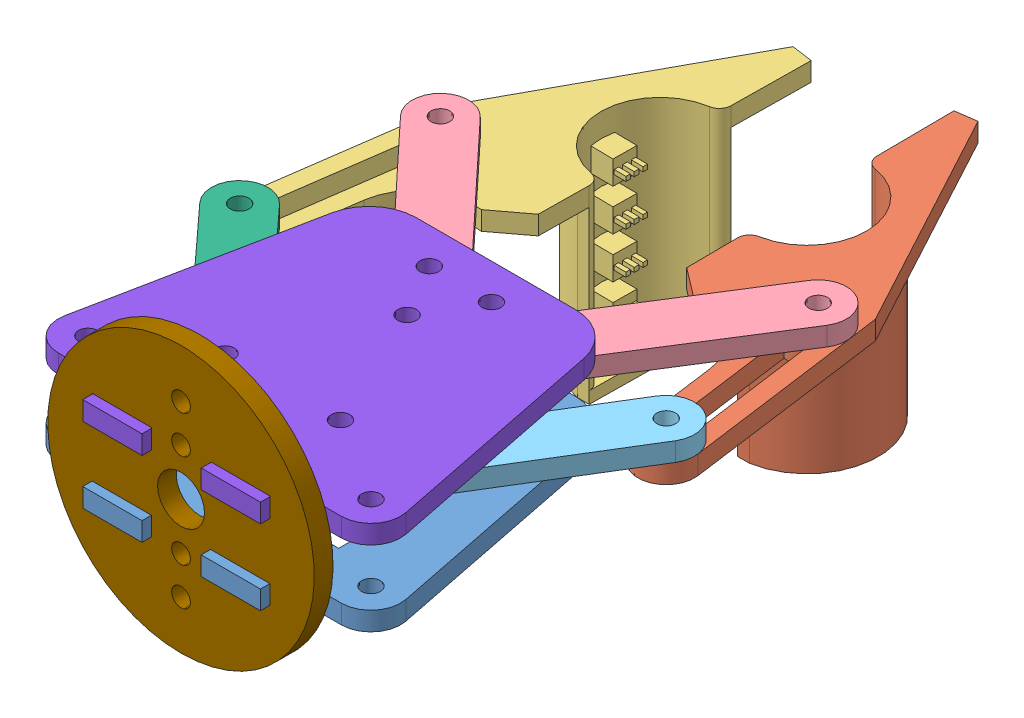
SolidWorks assembly Gripper2, configuration Predeterminado. Lengths in mm.
Overall size (91.5 56.15 127.82).
15 component instances, 9 part files, 33 mates.
Components (placement in the parent):
- Base grip-1: Base grip [Predeterminado] at (-28.7905 -8.0804 25) size (57.8 3.17 54.76)
- Gripp2-3: Gripp2 [Predeterminado] at (19.4575 -1.7304 -56.7394) x (-0.990815 0 0.135226) z (0.135226 0 0.990815) size (24.38 32 79.76)
- Gripp-3: Gripp [Predeterminado] at (-23.0143 -4.9054 -52.0769) x (0.99023 0 0.139447) z (-0.139447 0 0.99023) size (24.38 32 79.76)
- eslabon dos-1: eslabon dos [Predeterminado] at (13.1017 -1.7304 -38.4567) x (0.533516 0 -0.84579) z (0.84579 0 0.533516) size (49.52 3.17 9.53)
- eslabon dos-2: eslabon dos [Predeterminado] at (-14.2298 -1.7304 -36.8567) x (0.683322 0 0.730117) z (-0.730117 0 0.683322) size (49.52 3.17 9.53)
- eslabon engrane servo-1: eslabon engrane servo [Predeterminado] at (25.469 -1.7304 -3.5655) x (-0.522435 0 0.852679) z (-0.852679 0 -0.522435) size (56.02 3.17 23.48)
- eslabon engrane servo - copia-1: eslabon engrane servo - copia [Predeterminado] at (-18.5366 -1.7304 -6.9655) x (0.675407 0 0.737445) z (-0.737445 0 0.675407) size (56.51 3.17 22.67)
- separadores-1: separadores [Predeterminado] at (-8.5405 -4.9054 11) x (0.999665 0 -0.025874) z (0.025874 0 0.999665) size (6.35 3.17 6.35)
- separadores-2: separadores [Predeterminado] at (-8.5405 1.4446 11) x (0.999761 0 0.021872) z (-0.021872 0 0.999761) size (6.35 3.17 6.35)
- separadores-4: separadores [Predeterminado] at (-4.0405 -4.9054 -19) x (0.999761 0 0.021872) z (-0.021872 0 0.999761) size (6.35 3.17 6.35)
- separadores-5: separadores [Predeterminado] at (6.4595 1.4446 -19) x (0.999761 0 0.021872) z (-0.021872 0 0.999761) size (6.35 3.17 6.35)
- separadores-6: separadores [Predeterminado] at (-4.0405 1.4446 -19) x (0.999761 0 0.021872) z (-0.021872 0 0.999761) size (6.35 3.17 6.35)
- separadores-7: separadores [Predeterminado] at (6.4595 -4.9054 -19) x (0.999761 0 0.021872) z (-0.021872 0 0.999761) size (6.35 3.17 6.35)
- bse grip superior-2: bse grip superior [Predeterminado] at (-28.7905 4.6196 25) size (57.8 3.17 54.76)
- base gripper servo-1: base gripper servo [Predeterminado] at (1.2095 -0.0804 28.175) x (1 0 0) z (0 1 0) size (45 3.17 45)
Mates (geometry in assembly coordinates):
- Coincidente33: coincident aligned: axis of Base grip-1 through (-4.0405 -4.9054 -19) axis (0 -1 0); axis of eslabon dos-2 through (-4.0405 1.4446 -19) axis (0 -1 0)
- Coincidente38: coincident aligned: axis of Gripp-3 through (-31.3734 -1.7304 -48.2047) axis (0 -1 0); axis of eslabon dos-2 through (-31.3734 1.4446 -48.2047) axis (0 -1 0)
- Coincidente43: coincident anti-aligned: axis of Gripp2-3 through (27.8001 -4.9054 -52.8316) axis (0 1 0); axis of eslabon dos-1 through (27.8001 1.4446 -52.8316) axis (0 -1 0)
- Coincidente44: coincident aligned: axis of Base grip-1 through (6.4595 -4.9054 -19) axis (0 -1 0); axis of eslabon dos-1 through (6.4595 1.4446 -19) axis (0 -1 0)
- Coincidente46: coincident anti-aligned: plane of Gripp-3 through (-18.8469 -1.7304 -31.2926) normal (0 1 0); plane of eslabon dos-2 through (-31.3734 -1.7304 -48.2047) normal (0 -1 0)
- Coincidente49: coincident anti-aligned: plane of Gripp2-3 through (15.2016 -1.7304 -35.9731) normal (0 1 0); plane of eslabon dos-1 through (6.4595 -1.7304 -19) normal (0 -1 0)
- Coincidente55: coincident anti-aligned: axis of Gripp2-3 through (31.8569 -4.9054 -23.1072) axis (0 1 0); axis of eslabon engrane servo-1 through (31.8569 1.4446 -23.1072) axis (0 -1 0)
- Coincidente57: coincident anti-aligned: plane of Gripp2-3 through (15.2016 -1.7304 -35.9731) normal (0 1 0); plane of eslabon engrane servo-1 through (31.8569 -1.7304 -23.1072) normal (0 -1 0)
- Coincidente58: coincident aligned: axis of Gripp-3 through (-35.5568 -1.7304 -18.4978) axis (0 -1 0); axis of eslabon engrane servo - copia-1 through (-35.5568 1.4446 -18.4978) axis (0 -1 0)
- Coincidente61: coincident anti-aligned: plane of Gripp-3 through (-18.8469 -1.7304 -31.2926) normal (0 1 0); plane of eslabon engrane servo - copia-1 through (-35.5568 -1.7304 -18.4978) normal (0 -1 0)
- Coincidente65: coincident anti-aligned: axis of eslabon engrane servo - copia-1 through (-8.5405 -1.7304 11) axis (0 1 0); axis of separadores-1 through (-8.5405 -1.7304 11) axis (0 -1 0)
- Coincidente66: coincident anti-aligned: plane of eslabon engrane servo - copia-1 through (-35.5568 -1.7304 -18.4978) normal (0 -1 0); plane of separadores-1 through (-8.5405 -1.7304 11) normal (0 1 0)
- Coincidente67: coincident: moEndPointRef_w of separadores-1; axis of separadores-2 through (-8.5405 4.6196 11) axis (0 -1 0)
- Coincidente68: coincident anti-aligned: plane of eslabon engrane servo - copia-1 through (-35.5568 1.4446 -18.4978) normal (0 1 0); plane of separadores-2 through (-8.5405 1.4446 11) normal (0 -1 0)
- Coincidente69: coincident aligned: axis of eslabon dos-2 through (-4.0405 1.4446 -19) axis (0 -1 0); axis of separadores-4 through (-4.0405 -1.7304 -19) axis (0 -1 0)
- Coincidente70: coincident anti-aligned: plane of eslabon dos-2 through (-31.3734 -1.7304 -48.2047) normal (0 -1 0); plane of separadores-4 through (-4.0405 -1.7304 -19) normal (0 1 0)
- Coincidente71: coincident anti-aligned: plane of Base grip-1 through (14.651 -4.9054 -17) normal (0 1 0); plane of separadores-4 through (-4.0405 -4.9054 -19) normal (0 -1 0)
- Coincidente72: coincident anti-aligned: plane of eslabon dos-1 through (6.4595 -1.7304 -19) normal (0 -1 0); plane of separadores-7 through (6.4595 -1.7304 -19) normal (0 1 0)
- Coincidente74: coincident aligned: axis of eslabon dos-1 through (6.4595 1.4446 -19) axis (0 -1 0); axis of separadores-7 through (6.4595 -1.7304 -19) axis (0 -1 0)
- Coincidente77: coincident anti-aligned: plane of eslabon dos-2 through (-31.3734 1.4446 -48.2047) normal (0 1 0); plane of separadores-6 through (-4.0405 1.4446 -19) normal (0 -1 0)
- Coincidente78: coincident aligned: axis of eslabon dos-2 through (-4.0405 1.4446 -19) axis (0 -1 0); axis of separadores-6 through (-4.0405 4.6196 -19) axis (0 -1 0)
- Coincidente79: coincident anti-aligned: plane of eslabon dos-1 through (6.4595 1.4446 -19) normal (0 1 0); plane of separadores-5 through (6.4595 1.4446 -19) normal (0 -1 0)
- Coincidente80: coincident aligned: axis of eslabon dos-1 through (6.4595 1.4446 -19) axis (0 -1 0); axis of separadores-5 through (6.4595 4.6196 -19) axis (0 -1 0)
- Coincidente81: coincident anti-aligned: plane of Base grip-1 through (14.651 -4.9054 -17) normal (0 1 0); plane of separadores-7 through (6.4595 -4.9054 -19) normal (0 -1 0)
- Coincidente82: coincident aligned: axis of Base grip-1 through (-8.5405 -4.9054 11) axis (0 -1 0); axis of separadores-2 through (-8.5405 4.6196 11) axis (0 -1 0)
- Coincidente83: coincident aligned: axis of Base grip-1 through (-22.6915 -8.0804 20) axis (0 1 0); axis of bse grip superior-2 through (-22.6915 4.6196 20) axis (0 1 0)
- Coincidente84: coincident aligned: axis of Base grip-1 through (1.2095 -8.0804 -10) axis (0 1 0); axis of bse grip superior-2 through (1.2095 4.6196 -10) axis (0 1 0)
- Coincidente85: coincident anti-aligned: axis of eslabon engrane servo-1 through (10.9595 -1.7304 11) axis (0 1 0); axis of bse grip superior-2 through (10.9595 7.7946 11) axis (0 -1 0)
- Coincidente86: coincident anti-aligned: plane of separadores-2 through (-8.5405 4.6196 11) normal (0 1 0); plane of bse grip superior-2 through (14.651 4.6196 -17) normal (0 -1 0)
- Relación de posición de engranaje7: gear = 15 : 15 mm: axis of eslabon engrane servo - copia-1 through (-8.5405 -1.7304 11) axis (0 1 0); axis of eslabon engrane servo-1 through (10.9595 -1.7304 11) axis (0 1 0)
- Coincidente93: coincident anti-aligned: plane of Base grip-1 through (-28.7905 -4.9054 25) normal (0 0 1); plane of base gripper servo-1 through (1.2095 -0.0804 25) normal (0 0 -1)
- Coincidente94: coincident anti-aligned: plane of Base grip-1 through (-3.7905 -8.0804 25) normal (1 0 0); plane of base gripper servo-1 through (-3.7905 -8.0804 25) normal (-1 0 0)
- Coincidente95: coincident anti-aligned: plane of Base grip-1 through (14.651 -8.0804 -17) normal (0 -1 0); plane of base gripper servo-1 through (-13.7905 -8.0804 25) normal (0 1 0)
